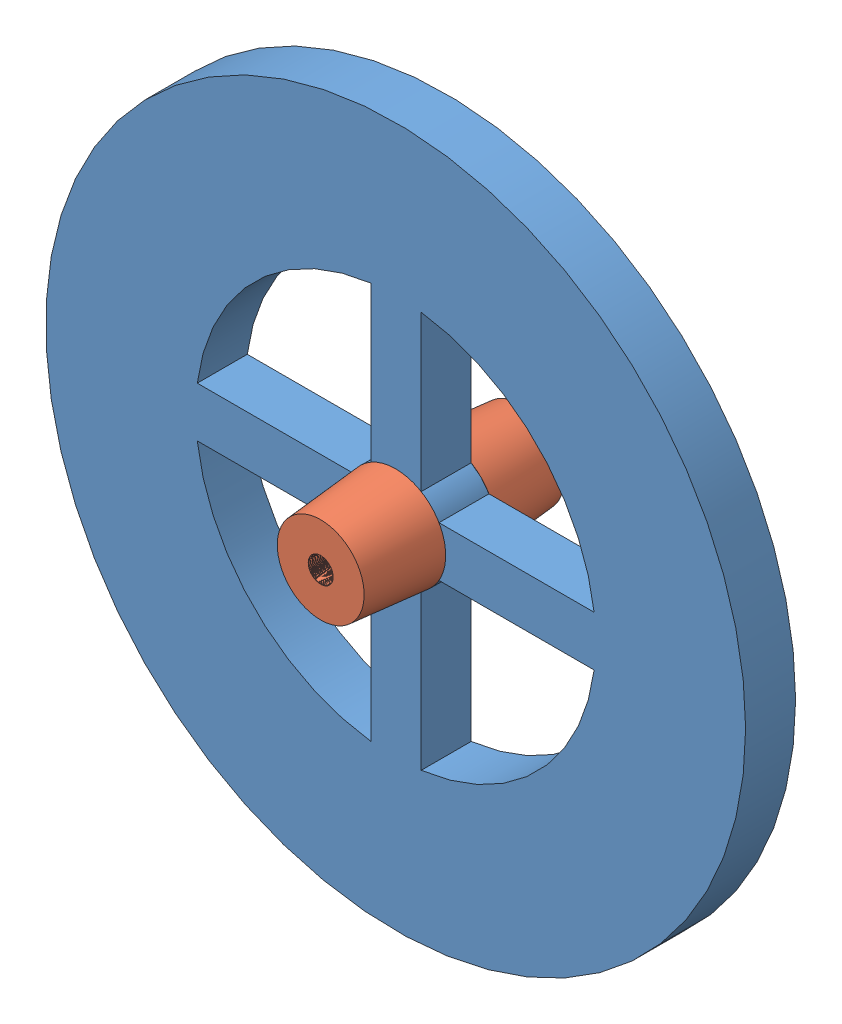
SolidWorks assembly ENTIRE WHEEL, configuration Default. Lengths in mm.
Overall size (355.6 355.6 101.6).
3 component instances, 2 part files, 4 mates.
Components (placement in the parent):
- Wheel-1: Wheel [Default] at origin size (355.6 355.6 25.68)
- WHEEL CAP-1: WHEEL CAP [Default] x (0.837507 0.546426 0) z (0 0 1) size (50.8 50.8 38.1)
- WHEEL CAP-2: WHEEL CAP [Default] at (0 0 -25.4) x (-0.52724 -0.849716 0) z (0 0 -1) size (50.8 50.8 38.1)
Mates (geometry in assembly coordinates):
- Coincident1: coincident: circle of WHEEL CAP-1; plane of assembly through (0 0 0) normal (0 0 1)
- Concentric1: concentric: circle of Wheel-1; circle of WHEEL CAP-1
- Concentric3: concentric: circle of Wheel-1; circle of WHEEL CAP-2
- Tangent5: tangent: plane of Wheel-1 through (0 0 -25.4) normal (0 0 -1); circle of WHEEL CAP-2
